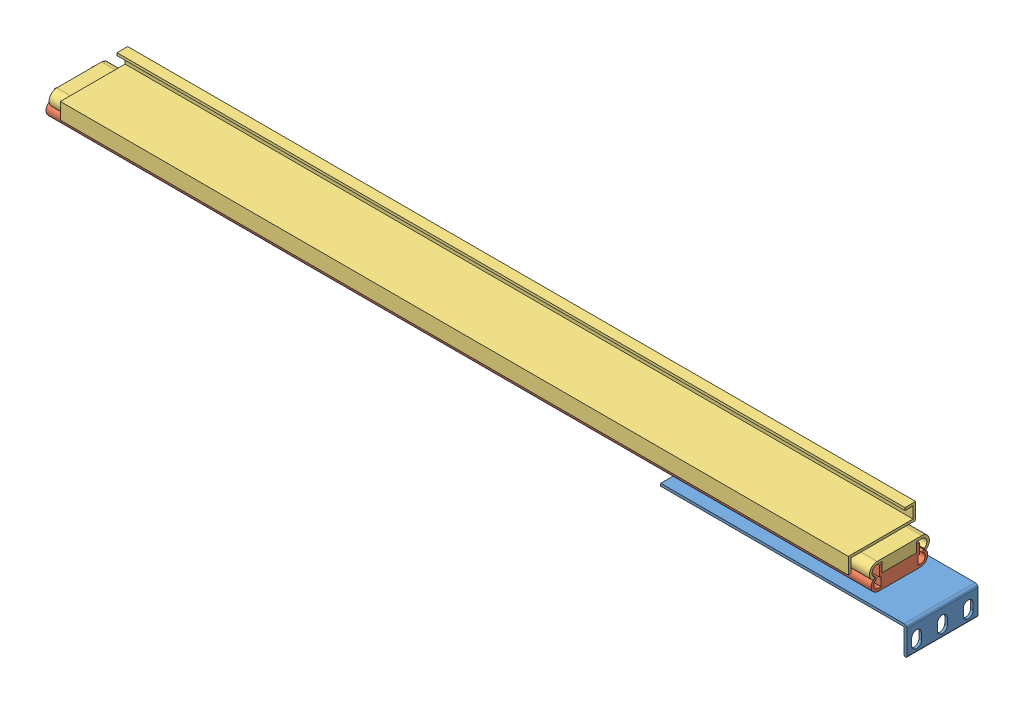
SolidWorks assembly Gleitschiene-Left, configuration Standard. Lengths in mm.
Overall size (537 44.1 44).
3 component instances, 3 part files, 7 mates.
Components (placement in the parent):
- winkel-1: winkel [Standard] at (51.9543 -6.5595 130.1) size (152.1 17.5 44)
- Schine-1: Schine [Standard] at (-484.2457 10.9405 134.15) x (0 1 0) z (1 0 0) size (13.6 35 510)
- Rolle-1: Rolle [Standard] at (-471.2457 35.9405 133.25) x (0 1 0) z (1 0 0) size (19.2 41.6 507)
Mates (geometry in assembly coordinates):
- Deckungsgleich1: coincident anti-aligned: plane of winkel-1 through (51.0043 10.9405 174.1) normal (0 1 0); plane of Schine-1 through (25.7543 10.9405 164.6513) normal (0 -1 0)
- Parallel1: parallel aligned: plane of winkel-1 through (52.7543 -5.7595 174.1) normal (1 0 0); plane of Schine-1 through (25.7543 15.4392 164.6513) normal (1 0 0)
- Abstand1: distance = 27 mm aligned: plane of winkel-1 through (52.7543 -5.7595 174.1) normal (1 0 0); plane of Schine-1 through (25.7543 15.4392 164.6513) normal (1 0 0)
- Abstand2: distance = 2 mm aligned: plane of Schine-1 through (25.7543 12.5405 163) normal (0 0 1); plane of winkel-1 through (8.7543 2.4905 165) normal (0 0 1)
- Deckungsgleich5: coincident anti-aligned: plane of Schine-1 through (25.7543 19.7405 141) normal (0 1 0); plane of Rolle-1 through (-481.2457 19.7405 162.3) normal (0 -1 0)
- Deckungsgleich6: coincident anti-aligned: plane of Schine-1 through (25.7543 24.5405 141) normal (0 0 1); plane of Rolle-1 through (-481.2457 19.7405 141) normal (0 0 -1)
- LimitAbstand1: limit distance = 0 mm aligned: plane of Rolle-1 through (25.7543 22.5716 165.45) normal (1 0 0); plane of Schine-1 through (25.7543 15.4392 164.6513) normal (1 0 0)
